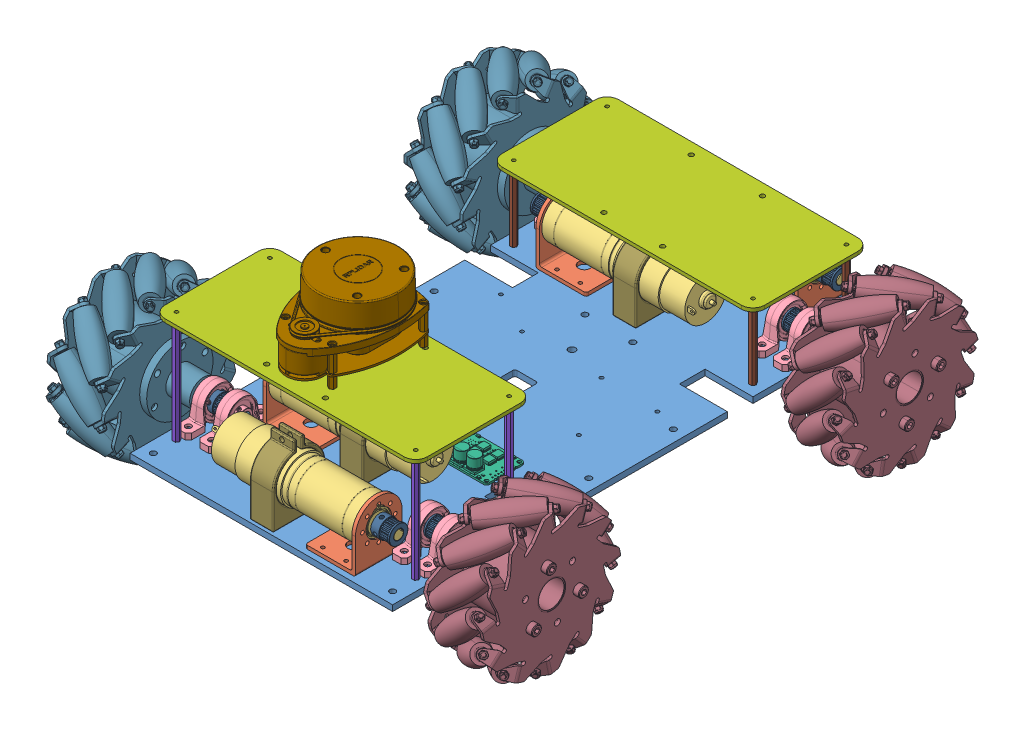
SolidWorks assembly Base plate and body, configuration Default. Lengths in mm.
Overall size (385.7 226 477.05).
49 component instances, 14 part files, 119 mates.
Components (placement in the parent):
- Base Plate-1: Base Plate [Default] at (160.2346 317.9651 819.6142) x (1 0 0) z (0 -1 0) size (225 428.62 5)
- Motor bracket-1: Motor bracket [Default] at (105.7346 317.9651 702.6142) x (0 0 -1) z (1 0 0) size (40 50 43)
- Motor bracket-4: Motor bracket [Default] at (214.7346 317.9651 629.9942) x (0 0 1) z (-1 0 0) size (40 50 43)
- planetary motor-1: planetary motor [Default] at (210.7346 347.9651 702.6142) x (0 1 0) z (0 0 1) size (38.5 150.5 38.49)
- planetary motor-3: planetary motor [Default] at (109.7346 347.9651 629.9942) x (0 -0.707107 -0.707107) z (0 -0.707107 0.707107) size (38.5 150.5 38.49)
- Pillow Block P08-3: Pillow Block P08 [Default] at (57.7346 332.9651 666.3042) x (0 0 1) z (-1 0 0) size (55 39.88 14.5)
- Pillow Block P08-18: Pillow Block P08 [Default] at (262.7346 332.9651 666.3042) x (0 0 -1) z (1 0 0) size (55 39.88 14.5)
- Pillow Block P08-5: Pillow Block P08 [Default] at (262.7346 332.9651 972.9242) x (0 0 -1) z (1 0 0) size (55 39.88 14.5)
- planetary motor-4: planetary motor [Default] at (109.7346 347.9651 1009.2342) x (0 -0.707107 0.707107) z (0 0.707107 0.707107) size (38.5 150.5 38.49)
- Motor bracket-3: Motor bracket [Default] at (214.7346 317.9651 1009.2342) x (0 0 1) z (-1 0 0) size (40 50 43)
- wheel axe-4: wheel axe [Default] at (247.7846 332.9651 972.9242) x (0 0.812189 -0.583394) z (1 0 0) size (8 8 73)
- wheel axe-1: wheel axe [Default] at (72.6846 332.9651 666.3042) x (0 -0.250872 -0.96802) z (-1 0 0) size (8 8 73)
- wheel axe-2: wheel axe [Default] at (247.7846 332.9651 666.3042) x (0 -0.625718 0.780049) z (1 0 0) size (8 8 73)
- wheel axe-8: wheel axe [Default] at (72.6846 332.9651 972.9242) x (0 -0.849321 0.527877) z (-1 0 0) size (8 8 73)
- Motor bracket-8: Motor bracket [Default] at (105.7346 317.9651 936.6142) x (0 0 -1) z (1 0 0) size (40 50 43)
- planetary motor-8: planetary motor [Default] at (210.7346 347.9651 936.6142) x (0 -0.707107 -0.707107) z (0 0.707107 -0.707107) size (38.5 150.5 38.49)
- Pillow Block P08-9: Pillow Block P08 [Default] at (57.7346 332.9651 972.9242) x (0 0 1) z (-1 0 0) size (55 39.88 14.5)
- MD13S-8: MD13S [Default] at (194.4964 317.9651 889.1442) x (-1 0 0) z (0 0 -1) size (60.96 12.27 33.02)
- Pillow Block P08-16: Pillow Block P08 [Default] at (242.7346 332.9651 666.3042) x (0 0 1) z (-1 0 0) size (55 39.88 14.5)
- Pillow Block P08-15: Pillow Block P08 [Default] at (77.7346 332.9651 666.3042) x (0 0 -1) z (1 0 0) size (55 39.88 14.5)
- Pillow Block P08-14: Pillow Block P08 [Default] at (242.7346 332.9651 972.9242) x (0 0 1) z (-1 0 0) size (55 39.88 14.5)
- Pillow Block P08-17: Pillow Block P08 [Default] at (77.7346 332.9651 972.9242) x (0 0 -1) z (1 0 0) size (55 39.88 14.5)
- mid level plate-1: mid level plate [Default] at (160.2346 409.9651 964.1142) size (225 3 100)
- 82mm spacer-3: 82mm spacer [Default] at (57.7346 317.9651 1004.1142) size (5.37 92 4.65)
- 82mm spacer-2: 82mm spacer [Default] at (262.7346 317.9651 1004.1142) x (0.536786 0 -0.843719) z (0.843719 0 0.536786) size (5.37 92 4.65)
- 82mm spacer-4: 82mm spacer [Default] at (262.7346 317.9651 924.1142) x (0.814654 0 -0.579948) z (0.579948 0 0.814654) size (5.37 92 4.65)
- 82mm spacer-5: 82mm spacer [Default] at (57.7346 317.9651 924.1142) size (5.37 92 4.65)
- RPLIDAR A1 DevKit.igs-1: RPLIDAR A1 DevKit.igs [Default] at (147.0194 421.8691 1020.526) x (-0.001508 0 0.999999) z (-0.999999 0 -0.001508) size (97.53 56.6 71.78)
- GT2_20Teeth_Pully-1: GT2_20Teeth_Pully [Default] at (76.1346 347.9651 702.6142) x (0 0.998416 0.056263) z (0 -0.056263 0.998416) size (16 16 16)
- GT2_20Teeth_Pully-2: GT2_20Teeth_Pully [Default] at (65.3346 332.9651 666.3042) x (0 -0.207664 -0.9782) z (0 -0.9782 0.207664) size (16 16 16)
- GT2_20Teeth_Pully-3: GT2_20Teeth_Pully [Default] at (255.1346 332.9651 666.3042) x (0 0.729948 -0.683503) z (0 0.683503 0.729948) size (16 16 16)
- GT2_20Teeth_Pully-4: GT2_20Teeth_Pully [Default] at (244.3346 347.9651 629.9942) x (0 1 0) z (0 0 -1) size (16 16 16)
- GT2_20Teeth_Pully-5: GT2_20Teeth_Pully [Default] at (76.1346 347.9651 936.6142) x (0 0.757797 0.652491) z (0 -0.652491 0.757797) size (16 16 16)
- GT2_20Teeth_Pully-6: GT2_20Teeth_Pully [Default] at (65.3346 332.9651 972.9242) x (0 0.931416 -0.363957) z (0 -0.363957 -0.931416) size (16 16 16)
- GT2_20Teeth_Pully-7: GT2_20Teeth_Pully [Default] at (244.3346 347.9651 1009.2342) x (0 0.247004 -0.969014) z (0 -0.969014 -0.247004) size (16 16 16)
- GT2_20Teeth_Pully-8: GT2_20Teeth_Pully [Default] at (255.1346 332.9651 972.9242) x (0 0.926158 0.377135) z (0 -0.377135 0.926158) size (16 16 16)
- 70mm spacer-8: 70mm spacer [Default] at (262.7346 317.9651 635.1142) size (5.37 60 4.65)
- 70mm spacer-7: 70mm spacer [Default] at (262.7346 317.9651 715.1142) size (5.37 60 4.65)
- 70mm spacer-10: 70mm spacer [Default] at (57.7346 317.9651 715.1142) size (5.37 60 4.65)
- 70mm spacer-9: 70mm spacer [Default] at (57.7346 317.9651 635.1142) size (5.37 60 4.65)
- mid level plate-2: mid level plate [Default] at (160.2346 377.9651 675.1142) size (225 3 100)
- motor support-1: motor support [Default] at (148.2346 347.9651 1009.2342) x (0 0 -1) z (1 0 0) size (45 59.2 20)
- motor support-2: motor support [Default] at (172.2346 347.9651 936.6142) x (0 0 1) z (-1 0 0) size (45 59.2 20)
- motor support-3: motor support [Default] at (172.2346 347.9651 702.6142) x (0 0 1) z (-1 0 0) size (45 59.2 20)
- motor support-4: motor support [Default] at (168.2346 347.9651 629.9942) x (0 0 1) z (-1 0 0) size (45 59.2 20)
- Mecanum wheel 127mm L-1: Mecanum wheel 127mm L [Default] at (183.1488 337.1152 954.9141) x (0 0.205272 -0.978705) z (1 0 0) size (136.87 136.87 82.4)
- Mecanum wheel 127mm L-2: Mecanum wheel 127mm L [Default] at (183.1488 315.5688 660.0629) x (0 -0.947736 -0.319055) z (1 0 0) size (136.87 136.87 82.4)
- Mecanum wheel 127mm R-1: Mecanum wheel 127mm R [Default] at (137.8056 342.8387 1026.7295) x (0 0.107749 0.994178) z (-1 0 0) size (132 132 82.4)
- Mecanum wheel 127mm R-2: Mecanum wheel 127mm R [Default] at (137.8056 382.9078 688.6252) x (0 0.880525 0.474) z (-1 0 0) size (132 132 82.4)
Mates (geometry in assembly coordinates):
- Coincident1: coincident anti-aligned: plane of Base Plate-1 through (160.2346 317.9651 819.6142) normal (0 1 0); plane of Motor bracket-1 through (105.7346 317.9651 702.6142) normal (0 -1 0)
- Coincident2: coincident anti-aligned: plane of Base Plate-1 through (160.2346 317.9651 819.6142) normal (0 1 0); plane of Motor bracket-4 through (214.7346 317.9651 629.9942) normal (0 -1 0)
- Coincident7: coincident anti-aligned: plane of Motor bracket-1 through (87.2346 347.9651 702.6142) normal (1 0 0); plane of planetary motor-1 through (87.2346 347.9651 702.6142) normal (-1 0 0)
- Concentric8: concentric aligned: cylinder of Motor bracket-1 through (87.2346 357.8646 692.7147) axis (-1 0 0) radius 1.6; cylinder of planetary motor-1 through (107.2346 357.8646 692.7147) axis (-1 0 0) radius 2
- Concentric9: concentric anti-aligned: circle of Motor bracket-1; circle of planetary motor-1
- Coincident8: coincident anti-aligned: plane of Motor bracket-4 through (233.2346 347.9651 629.9942) normal (-1 0 0); plane of planetary motor-3 through (233.2346 347.9651 629.9942) normal (1 0 0)
- Concentric10: concentric aligned: cylinder of Motor bracket-4 through (233.2346 357.8646 639.8937) axis (1 0 0) radius 1.6; cylinder of planetary motor-3 through (228.2346 357.8646 639.8937) axis (1 0 0) radius 2.5
- Concentric11: concentric aligned: cylinder of Motor bracket-4 through (233.2346 361.9651 629.9942) axis (1 0 0) radius 1.6; cylinder of planetary motor-3 through (213.2346 361.9651 629.9942) axis (1 0 0) radius 2
- Concentric12: concentric aligned: cylinder of Motor bracket-3 through (233.2346 361.9651 1009.2342) axis (1 0 0) radius 1.6; cylinder of planetary motor-4 through (213.2346 361.9651 1009.2342) axis (1 0 0) radius 2
- Concentric13: concentric aligned: cylinder of Motor bracket-3 through (233.2346 357.8646 1019.1337) axis (1 0 0) radius 1.6; cylinder of planetary motor-4 through (228.2346 357.8646 1019.1337) axis (1 0 0) radius 2.5
- Coincident20: coincident anti-aligned: plane of Motor bracket-3 through (233.2346 347.9651 1009.2342) normal (-1 0 0); plane of planetary motor-4 through (233.2346 347.9651 1009.2342) normal (1 0 0)
- Concentric55: concentric anti-aligned: cylinder of Base Plate-1 through (262.7346 322.9651 993.9242) axis (0 -1 0) radius 2.5; cylinder of Pillow Block P08-5 through (262.7346 316.9651 993.9242) axis (0 1 0) radius 2.5
- Parallel4: parallel anti-aligned: plane of Base Plate-1 through (160.2346 317.9651 819.6142) normal (0 1 0); plane of Pillow Block P08-5 through (262.7346 317.9651 972.9242) normal (0 -1 0)
- Concentric59: concentric anti-aligned: cylinder of Base Plate-1 through (262.7346 322.9651 687.3042) axis (0 -1 0) radius 2.5; cylinder of Pillow Block P08-18 through (262.7346 316.9651 687.3042) axis (0 1 0) radius 2.5
- Parallel5: parallel anti-aligned: plane of Base Plate-1 through (160.2346 317.9651 819.6142) normal (0 1 0); plane of Pillow Block P08-18 through (262.7346 317.9651 666.3042) normal (0 -1 0)
- Concentric64: concentric aligned: cylinder of Pillow Block P08-18 through (254.4974 332.9651 666.3042) axis (-1 0 0) radius 4; cylinder of wheel axe-2 through (307.7846 332.9651 666.3042) axis (-1 0 0) radius 4
- Concentric66: concentric aligned: cylinder of Pillow Block P08-5 through (254.4974 332.9651 972.9242) axis (-1 0 0) radius 4; cylinder of wheel axe-4 through (307.7846 332.9651 972.9242) axis (-1 0 0) radius 4
- Coincident30: coincident anti-aligned: plane of Base Plate-1 through (160.2346 317.9651 819.6142) normal (0 1 0); plane of Motor bracket-3 through (214.7346 317.9651 1009.2342) normal (0 -1 0)
- Coincident31: coincident anti-aligned: plane of Base Plate-1 through (160.2346 317.9651 819.6142) normal (0 1 0); plane of Pillow Block P08-5 through (262.7346 317.9651 972.9242) normal (0 -1 0)
- Concentric68: concentric anti-aligned: cylinder of Base Plate-1 through (262.7346 322.9651 951.9242) axis (0 -1 0) radius 2.5; cylinder of Pillow Block P08-5 through (262.7346 316.9651 951.9242) axis (0 1 0) radius 2.5
- Concentric81: concentric aligned: cylinder of Motor bracket-8 through (87.2346 361.9651 936.6142) axis (-1 0 0) radius 1.6; cylinder of planetary motor-8 through (107.2346 361.9651 936.6142) axis (-1 0 0) radius 2
- Concentric82: concentric aligned: cylinder of Motor bracket-8 through (87.2346 357.8646 926.7147) axis (-1 0 0) radius 1.6; cylinder of planetary motor-8 through (92.2346 357.8646 926.7147) axis (-1 0 0) radius 2.5
- Coincident41: coincident anti-aligned: plane of Motor bracket-8 through (87.2346 347.9651 936.6142) normal (1 0 0); plane of planetary motor-8 through (87.2346 347.9651 936.6142) normal (-1 0 0)
- Concentric83: concentric aligned: cylinder of wheel axe-8 through (12.6846 332.9651 972.9242) axis (1 0 0) radius 4; cylinder of Pillow Block P08-9 through (65.9718 332.9651 972.9242) axis (1 0 0) radius 4
- Parallel8: parallel anti-aligned: plane of Base Plate-1 through (160.2346 317.9651 819.6142) normal (0 1 0); plane of Pillow Block P08-9 through (57.7346 317.9651 972.9242) normal (0 -1 0)
- Coincident43: coincident anti-aligned: plane of Base Plate-1 through (160.2346 317.9651 819.6142) normal (0 1 0); plane of Motor bracket-8 through (105.7346 317.9651 936.6142) normal (0 -1 0)
- Coincident44: coincident anti-aligned: plane of Base Plate-1 through (160.2346 317.9651 819.6142) normal (0 1 0); plane of Pillow Block P08-9 through (57.7346 317.9651 972.9242) normal (0 -1 0)
- Concentric99: concentric anti-aligned: cylinder of wheel axe-4 through (307.7846 332.9651 972.9242) axis (-1 0 0) radius 4; cylinder of wheel axe-8 through (12.6846 332.9651 972.9242) axis (1 0 0) radius 4
- Coincident81: coincident anti-aligned: plane of Base Plate-1 through (160.2346 317.9651 819.6142) normal (0 1 0); plane of Pillow Block P08-3 through (57.7346 317.9651 666.3042) normal (0 -1 0)
- Concentric122: concentric anti-aligned: cylinder of Base Plate-1 through (57.7346 322.9651 993.9242) axis (0 -1 0) radius 2.5; cylinder of Pillow Block P08-9 through (57.7346 316.9651 993.9242) axis (0 1 0) radius 2.5
- Coincident108: coincident anti-aligned: plane of Base Plate-1 through (160.2346 317.9651 819.6142) normal (0 1 0); plane of Pillow Block P08-18 through (262.7346 317.9651 666.3042) normal (0 -1 0)
- Concentric138: concentric anti-aligned: cylinder of Base Plate-1 through (262.7346 322.9651 645.3042) axis (0 -1 0) radius 2.5; cylinder of Pillow Block P08-18 through (262.7346 316.9651 645.3042) axis (0 1 0) radius 2.5
- Concentric139: concentric anti-aligned: cylinder of wheel axe-2 through (307.7846 332.9651 666.3042) axis (-1 0 0) radius 4; cylinder of Pillow Block P08-16 through (250.9718 332.9651 666.3042) axis (1 0 0) radius 4
- Coincident109: coincident anti-aligned: plane of Base Plate-1 through (160.2346 317.9651 819.6142) normal (0 1 0); plane of Pillow Block P08-16 through (242.7346 317.9651 666.3042) normal (0 -1 0)
- Coincident112: coincident anti-aligned: plane of Base Plate-1 through (160.2346 317.9651 819.6142) normal (0 1 0); plane of Pillow Block P08-15 through (77.7346 317.9651 666.3042) normal (0 -1 0)
- Concentric140: concentric anti-aligned: cylinder of wheel axe-1 through (12.6846 332.9651 666.3042) axis (1 0 0) radius 4; cylinder of Pillow Block P08-15 through (69.4974 332.9651 666.3042) axis (-1 0 0) radius 4
- Coincident114: coincident anti-aligned: plane of Base Plate-1 through (160.2346 317.9651 819.6142) normal (0 1 0); plane of Pillow Block P08-14 through (242.7346 317.9651 972.9242) normal (0 -1 0)
- Concentric141: concentric aligned: cylinder of wheel axe-4 through (307.7846 332.9651 972.9242) axis (1 0 0) radius 4; cylinder of Pillow Block P08-14 through (250.9718 332.9651 972.9242) axis (1 0 0) radius 4
- Concentric142: concentric anti-aligned: cylinder of wheel axe-8 through (12.6846 332.9651 972.9242) axis (1 0 0) radius 4; cylinder of Pillow Block P08-17 through (69.4974 332.9651 972.9242) axis (-1 0 0) radius 4
- Coincident121: coincident anti-aligned: plane of Base Plate-1 through (160.2346 317.9651 819.6142) normal (0 1 0); plane of Pillow Block P08-17 through (77.7346 317.9651 972.9242) normal (0 -1 0)
- Coincident152: coincident anti-aligned: plane of Base Plate-1 through (160.2346 317.9651 819.6142) normal (0 1 0); plane of 82mm spacer-3 through (57.7346 317.9651 1004.1142) normal (0 -1 0)
- Coincident153: coincident anti-aligned: plane of Base Plate-1 through (160.2346 317.9651 819.6142) normal (0 1 0); plane of 82mm spacer-2 through (262.7346 317.9651 1004.1142) normal (0 -1 0)
- Coincident154: coincident aligned: plane of 82mm spacer-2 through (262.7346 409.9651 1004.1142) normal (0 1 0); plane of 82mm spacer-4 through (262.7346 409.9651 924.1142) normal (0 1 0)
- Concentric161: concentric aligned: cylinder of Base Plate-1 through (262.7346 322.9651 924.1142) axis (0 -1 0) radius 1.5; cylinder of 82mm spacer-4 through (262.7346 409.9651 924.1142) axis (0 -1 0) radius 1.5
- Concentric162: concentric aligned: cylinder of mid level plate-1 through (57.7346 412.9651 924.1142) axis (0 -1 0) radius 1.5; cylinder of 82mm spacer-5 through (57.7346 409.9651 924.1142) axis (0 -1 0) radius 1.5
- Coincident155: coincident anti-aligned: plane of mid level plate-1 through (160.2346 409.9651 964.1142) normal (0 -1 0); plane of 82mm spacer-5 through (57.7346 409.9651 924.1142) normal (0 1 0)
- Coincident156: coincident anti-aligned: plane of Base Plate-1 through (160.2346 317.9651 819.6142) normal (0 1 0); plane of 82mm spacer-5 through (57.7346 317.9651 924.1142) normal (0 -1 0)
- Coincident164: coincident anti-aligned: plane of mid level plate-1 through (160.2346 412.9651 964.1142) normal (0 1 0); plane of RPLIDAR A1 DevKit.igs-1 through (188.2324 412.9651 923.1142) normal (0 -1 0)
- Concentric163: concentric anti-aligned: cylinder of Base Plate-1 through (242.7346 322.9651 993.9242) axis (0 -1 0) radius 2.5; cylinder of Pillow Block P08-14 through (242.7346 316.9651 993.9242) axis (0 1 0) radius 2.5
- Concentric173: concentric anti-aligned: cylinder of Base Plate-1 through (97.2346 307.9651 687.6142) axis (0 1 0) radius 1.5; cylinder of Motor bracket-1 through (97.2346 320.9651 687.6142) axis (0 -1 0) radius 1.5
- Concentric174: concentric anti-aligned: cylinder of Base Plate-1 through (117.2346 307.9651 687.6142) axis (0 1 0) radius 1.5; cylinder of Motor bracket-1 through (117.2346 320.9651 687.6142) axis (0 -1 0) radius 1.5
- Concentric175: concentric anti-aligned: cylinder of Base Plate-1 through (223.2346 307.9651 1024.2342) axis (0 1 0) radius 1.5; cylinder of Motor bracket-3 through (223.2346 320.9651 1024.2342) axis (0 -1 0) radius 1.5
- Concentric176: concentric anti-aligned: cylinder of Motor bracket-8 through (97.2346 320.9651 921.6142) axis (0 -1 0) radius 1.5; cylinder of Base Plate-1 through (97.2346 307.9651 921.6142) axis (0 1 0) radius 1.5
- Concentric177: concentric anti-aligned: cylinder of Base Plate-1 through (77.7346 322.9651 993.9242) axis (0 -1 0) radius 2.5; cylinder of Pillow Block P08-17 through (77.7346 316.9651 993.9242) axis (0 1 0) radius 2.5
- Concentric178: concentric aligned: cylinder of Pillow Block P08-3 through (65.9718 332.9651 666.3042) axis (1 0 0) radius 4; cylinder of wheel axe-1 through (12.6846 332.9651 666.3042) axis (1 0 0) radius 4
- Coincident183: coincident aligned: plane of wheel axe-4 through (234.7846 332.9651 972.9242) normal (-1 0 0); plane of Pillow Block P08-14 through (234.7846 331.3141 969.2809) normal (-1 0 0)
- Concentric179: concentric aligned: cylinder of wheel axe-4 through (307.7846 332.9651 972.9242) axis (-1 0 0) radius 4; cylinder of GT2_20Teeth_Pully-8 through (262.2346 332.9651 972.9242) axis (-1 0 0) radius 4
- Concentric180: concentric anti-aligned: cylinder of planetary motor-4 through (253.2346 347.9651 1009.2342) axis (-1 0 0) radius 4; cylinder of GT2_20Teeth_Pully-7 through (237.2346 347.9651 1009.2342) axis (1 0 0) radius 4
- Concentric181: concentric anti-aligned: cylinder of planetary motor-8 through (67.2346 347.9651 936.6142) axis (1 0 0) radius 4; cylinder of GT2_20Teeth_Pully-5 through (83.2346 347.9651 936.6142) axis (-1 0 0) radius 4
- Concentric182: concentric aligned: cylinder of wheel axe-8 through (12.6846 332.9651 972.9242) axis (1 0 0) radius 4; cylinder of GT2_20Teeth_Pully-6 through (58.2346 332.9651 972.9242) axis (1 0 0) radius 4
- Coincident184: coincident aligned: plane of wheel axe-8 through (85.6846 332.9651 972.9242) normal (1 0 0); plane of Pillow Block P08-17 through (85.6846 331.3141 976.5676) normal (1 0 0)
- Coincident185: coincident aligned: plane of wheel axe-1 through (85.6846 332.9651 666.3042) normal (1 0 0); plane of Pillow Block P08-15 through (85.6846 331.3141 669.9476) normal (1 0 0)
- Concentric183: concentric anti-aligned: cylinder of planetary motor-1 through (67.2346 347.9651 702.6142) axis (1 0 0) radius 4; cylinder of GT2_20Teeth_Pully-1 through (83.2346 347.9651 702.6142) axis (-1 0 0) radius 4
- Coincident186: coincident aligned: plane of planetary motor-1 through (67.2346 347.9651 702.6142) normal (-1 0 0); plane of GT2_20Teeth_Pully-1 through (67.2346 347.9651 702.6142) normal (-1 0 0)
- Concentric184: concentric aligned: cylinder of wheel axe-1 through (12.6846 332.9651 666.3042) axis (1 0 0) radius 4; cylinder of GT2_20Teeth_Pully-2 through (58.2346 332.9651 666.3042) axis (1 0 0) radius 4
- Coincident187: coincident aligned: plane of wheel axe-2 through (234.7846 332.9651 666.3042) normal (-1 0 0); plane of Pillow Block P08-16 through (234.7846 331.3141 662.6609) normal (-1 0 0)
- Concentric185: concentric aligned: cylinder of wheel axe-2 through (307.7846 332.9651 666.3042) axis (-1 0 0) radius 4; cylinder of GT2_20Teeth_Pully-3 through (262.2346 332.9651 666.3042) axis (-1 0 0) radius 4
- Concentric186: concentric anti-aligned: cylinder of planetary motor-3 through (253.2346 347.9651 629.9942) axis (-1 0 0) radius 4; cylinder of GT2_20Teeth_Pully-4 through (237.2346 347.9651 629.9942) axis (1 0 0) radius 4
- Concentric187: concentric anti-aligned: cylinder of Base Plate-1 through (203.2346 307.9651 994.2342) axis (0 1 0) radius 1.5; cylinder of Motor bracket-3 through (203.2346 320.9651 994.2342) axis (0 -1 0) radius 1.5
- Coincident188: coincident aligned: plane of planetary motor-4 through (253.2346 347.9651 1009.2342) normal (1 0 0); plane of GT2_20Teeth_Pully-7 through (253.2346 347.9651 1009.2342) normal (1 0 0)
- Coincident189: coincident aligned: plane of planetary motor-8 through (67.2346 347.9651 936.6142) normal (-1 0 0); plane of GT2_20Teeth_Pully-5 through (67.2346 347.9651 936.6142) normal (-1 0 0)
- Coincident190: coincident aligned: plane of planetary motor-3 through (253.2346 347.9651 629.9942) normal (1 0 0); plane of GT2_20Teeth_Pully-4 through (253.2346 347.9651 629.9942) normal (1 0 0)
- Concentric188: concentric anti-aligned: cylinder of Base Plate-1 through (242.7346 322.9651 687.3042) axis (0 -1 0) radius 2.5; cylinder of Pillow Block P08-16 through (242.7346 316.9651 687.3042) axis (0 1 0) radius 2.5
- Concentric190: concentric anti-aligned: cylinder of Base Plate-1 through (57.7346 322.9651 687.3042) axis (0 -1 0) radius 2.5; cylinder of Pillow Block P08-3 through (57.7346 316.9651 687.3042) axis (0 1 0) radius 2.5
- Concentric191: concentric anti-aligned: cylinder of Base Plate-1 through (77.7346 322.9651 645.3042) axis (0 -1 0) radius 2.5; cylinder of Pillow Block P08-15 through (77.7346 316.9651 645.3042) axis (0 1 0) radius 2.5
- Concentric192: concentric anti-aligned: cylinder of Base Plate-1 through (203.2346 307.9651 614.9942) axis (0 1 0) radius 1.5; cylinder of Motor bracket-4 through (203.2346 320.9651 614.9942) axis (0 -1 0) radius 1.5
- Concentric193: concentric anti-aligned: cylinder of Base Plate-1 through (117.2346 307.9651 921.6142) axis (0 1 0) radius 1.5; cylinder of Motor bracket-8 through (117.2346 320.9651 921.6142) axis (0 -1 0) radius 1.5
- Concentric196: concentric anti-aligned: cylinder of Base Plate-1 through (166.5564 372.9651 875.1742) axis (0 -1 0) radius 1.5; cylinder of MD13S-8 through (166.5564 317.9651 875.1742) axis (0 1 0) radius 1.5
- Parallel9: parallel anti-aligned: cylinder of Base Plate-1 through (222.4364 372.9651 875.1742) axis (0 -1 0) radius 1.5; cylinder of MD13S-8 through (222.4364 317.9651 875.1742) axis (0 1 0) radius 1.5
- Concentric198: concentric anti-aligned: cylinder of Base Plate-1 through (222.4364 372.9651 875.1742) axis (0 -1 0) radius 1.5; cylinder of MD13S-8 through (222.4364 317.9651 875.1742) axis (0 1 0) radius 1.5
- Concentric199: concentric aligned: cylinder of mid level plate-1 through (57.7346 412.9651 1004.1142) axis (0 -1 0) radius 1.5; cylinder of 82mm spacer-3 through (57.7346 409.9651 1004.1142) axis (0 -1 0) radius 1.5
- Concentric200: concentric aligned: cylinder of mid level plate-1 through (262.7346 412.9651 1004.1142) axis (0 -1 0) radius 1.5; cylinder of 82mm spacer-2 through (262.7346 409.9651 1004.1142) axis (0 -1 0) radius 1.5
- Concentric201: concentric aligned: cylinder of mid level plate-1 through (262.7346 412.9651 924.1142) axis (0 -1 0) radius 1.5; cylinder of 82mm spacer-4 through (262.7346 409.9651 924.1142) axis (0 -1 0) radius 1.5
- Concentric202: concentric aligned: cylinder of Base Plate-1 through (57.7346 322.9651 1004.1142) axis (0 -1 0) radius 1.5; cylinder of 82mm spacer-3 through (57.7346 409.9651 1004.1142) axis (0 -1 0) radius 1.5
- Concentric205: concentric aligned: cylinder of 70mm spacer-7 through (262.7346 377.9651 715.1142) axis (0 -1 0) radius 1.5; cylinder of mid level plate-2 through (262.7346 380.9651 715.1142) axis (0 -1 0) radius 1.5
- Concentric206: concentric aligned: cylinder of 70mm spacer-8 through (262.7346 377.9651 635.1142) axis (0 -1 0) radius 1.5; cylinder of mid level plate-2 through (262.7346 380.9651 635.1142) axis (0 -1 0) radius 1.5
- Concentric207: concentric aligned: cylinder of 70mm spacer-10 through (57.7346 377.9651 715.1142) axis (0 -1 0) radius 1.5; cylinder of mid level plate-2 through (57.7346 380.9651 715.1142) axis (0 -1 0) radius 1.5
- Concentric208: concentric aligned: cylinder of 70mm spacer-9 through (57.7346 377.9651 635.1142) axis (0 -1 0) radius 1.5; cylinder of mid level plate-2 through (57.7346 380.9651 635.1142) axis (0 -1 0) radius 1.5
- Coincident191: coincident aligned: plane of 70mm spacer-10 through (57.7346 377.9651 715.1142) normal (0 1 0); plane of 70mm spacer-9 through (57.7346 377.9651 635.1142) normal (0 1 0)
- Coincident192: coincident aligned: plane of 70mm spacer-7 through (262.7346 377.9651 715.1142) normal (0 1 0); plane of 70mm spacer-10 through (57.7346 377.9651 715.1142) normal (0 1 0)
- Coincident193: coincident aligned: plane of 70mm spacer-8 through (262.7346 377.9651 635.1142) normal (0 1 0); plane of 70mm spacer-7 through (262.7346 377.9651 715.1142) normal (0 1 0)
- Coincident194: coincident anti-aligned: plane of 70mm spacer-8 through (262.7346 377.9651 635.1142) normal (0 1 0); plane of mid level plate-2 through (160.2346 377.9651 675.1142) normal (0 -1 0)
- Coincident195: coincident anti-aligned: plane of Base Plate-1 through (160.2346 317.9651 819.6142) normal (0 1 0); plane of 70mm spacer-8 through (262.7346 317.9651 635.1142) normal (0 -1 0)
- Concentric209: concentric aligned: cylinder of Base Plate-1 through (262.7346 322.9651 635.1142) axis (0 -1 0) radius 1.5; cylinder of mid level plate-2 through (262.7346 380.9651 635.1142) axis (0 -1 0) radius 1.5
- Concentric210: concentric aligned: cylinder of Base Plate-1 through (262.7346 322.9651 715.1142) axis (0 -1 0) radius 1.5; cylinder of 70mm spacer-7 through (262.7346 377.9651 715.1142) axis (0 -1 0) radius 1.5
- Concentric212: concentric anti-aligned: cylinder of planetary motor-1 through (188.2346 347.9651 702.6142) axis (-1 0 0) radius 19.25; cylinder of motor support-3 through (152.2346 347.9651 702.6142) axis (1 0 0) radius 19.3
- Concentric213: concentric anti-aligned: cylinder of planetary motor-8 through (188.2346 347.9651 936.6142) axis (-1 0 0) radius 19.25; cylinder of motor support-2 through (152.2346 347.9651 936.6142) axis (1 0 0) radius 19.3
- Concentric214: concentric anti-aligned: cylinder of planetary motor-4 through (132.2346 347.9651 1009.2342) axis (1 0 0) radius 19.25; cylinder of motor support-1 through (168.2346 347.9651 1009.2342) axis (-1 0 0) radius 19.3
- Concentric215: concentric anti-aligned: cylinder of Base Plate-1 through (158.2346 307.9651 1009.2342) axis (0 1 0) radius 2.5; cylinder of motor support-1 through (158.2346 340.9651 1009.2342) axis (0 -1 0) radius 2.5
- Concentric217: concentric anti-aligned: cylinder of Base Plate-1 through (162.2346 307.9651 936.6142) axis (0 1 0) radius 2.5; cylinder of motor support-2 through (162.2346 340.9651 936.6142) axis (0 -1 0) radius 2.5
- Concentric219: concentric anti-aligned: cylinder of Base Plate-1 through (162.2346 307.9651 702.6142) axis (0 1 0) radius 2.5; cylinder of motor support-3 through (162.2346 340.9651 702.6142) axis (0 -1 0) radius 2.5
- Concentric223: concentric anti-aligned: cylinder of Base Plate-1 through (158.2346 307.9651 629.9942) axis (0 1 0) radius 2.5; cylinder of motor support-4 through (158.2346 340.9651 629.9942) axis (0 -1 0) radius 2.5
- Concentric225: concentric anti-aligned: cylinder of Base Plate-1 through (158.2346 307.9651 629.9942) axis (0 1 0) radius 2.5; cylinder of motor support-4 through (158.2346 340.9651 629.9942) axis (0 -1 0) radius 2.5
- Concentric229: concentric aligned: cylinder of wheel axe-8 through (12.6846 332.9651 972.9242) axis (1 0 0) radius 4; cylinder of Mecanum wheel 127mm R-1 through (-27.2154 332.9651 972.9242) axis (1 0 0) radius 10.95
- Coincident205: coincident anti-aligned: plane of Pillow Block P08-9 through (49.7846 331.3141 969.2809) normal (-1 0 0); plane of Mecanum wheel 127mm R-1 through (49.7846 332.9651 972.9242) normal (1 0 0)
- Concentric230: concentric aligned: cylinder of wheel axe-1 through (12.6846 332.9651 666.3042) axis (1 0 0) radius 4; cylinder of Mecanum wheel 127mm R-2 through (-25.1154 332.9651 666.3042) axis (1 0 0) radius 9.05
- Coincident206: coincident anti-aligned: plane of Pillow Block P08-3 through (49.7846 331.3141 662.6609) normal (-1 0 0); plane of Mecanum wheel 127mm R-2 through (49.7846 332.9651 666.3042) normal (1 0 0)
- Concentric231: concentric anti-aligned: cylinder of wheel axe-2 through (307.7846 332.9651 666.3042) axis (-1 0 0) radius 4; cylinder of Mecanum wheel 127mm L-2 through (297.4846 332.9651 666.3042) axis (1 0 0) radius 10.925
- Coincident207: coincident anti-aligned: plane of Pillow Block P08-18 through (270.6846 331.3141 669.9476) normal (1 0 0); plane of Mecanum wheel 127mm L-2 through (270.6846 332.9651 666.3042) normal (-1 0 0)
- Concentric232: concentric anti-aligned: cylinder of wheel axe-4 through (307.7846 332.9651 972.9242) axis (-1 0 0) radius 4; cylinder of Mecanum wheel 127mm L-1 through (297.4846 332.9651 972.9242) axis (1 0 0) radius 10.925
- Coincident208: coincident anti-aligned: plane of Pillow Block P08-5 through (270.6846 331.3141 976.5676) normal (1 0 0); plane of Mecanum wheel 127mm L-1 through (270.6846 332.9651 972.9242) normal (-1 0 0)
- Lock1: lock: unknown of mid level plate-1; unknown of RPLIDAR A1 DevKit.igs-1
- Coincident210: coincident anti-aligned: plane of Base Plate-1 through (160.2346 317.9651 819.6142) normal (0 1 0); plane of MD13S-8 through (194.4964 317.9651 889.1442) normal (0 -1 0)
- Coincident212: coincident anti-aligned: plane of Pillow Block P08-17 through (74.2346 331.3141 976.5676) normal (-1 0 0); plane of GT2_20Teeth_Pully-6 through (74.2346 332.9651 972.9242) normal (1 0 0)
- Coincident213: coincident anti-aligned: plane of Pillow Block P08-14 through (246.2346 331.3141 969.2809) normal (1 0 0); plane of GT2_20Teeth_Pully-8 through (246.2346 332.9651 972.9242) normal (-1 0 0)
- Coincident214: coincident anti-aligned: plane of Pillow Block P08-15 through (74.2346 331.3141 669.9476) normal (-1 0 0); plane of GT2_20Teeth_Pully-2 through (74.2346 332.9651 666.3042) normal (1 0 0)
- Coincident215: coincident anti-aligned: plane of Pillow Block P08-16 through (246.2346 331.3141 662.6609) normal (1 0 0); plane of GT2_20Teeth_Pully-3 through (246.2346 332.9651 666.3042) normal (-1 0 0)
- Concentric236: concentric aligned: cylinder of planetary motor-3 through (132.2346 347.9651 629.9942) axis (1 0 0) radius 19.25; cylinder of motor support-4 through (148.2346 347.9651 629.9942) axis (1 0 0) radius 19.3
- Tangent1: tangent anti-aligned: plane of Base Plate-1 through (221.7346 307.9651 619.9942) normal (1 0 0); cylinder of Motor bracket-4 through (223.2346 320.9651 614.9942) axis (0 -1 0) radius 1.5
